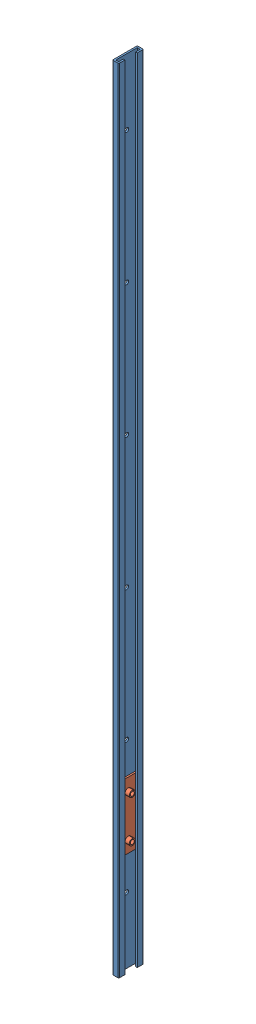
SolidWorks assembly Assem2, configuration Default. Lengths in mm.
Overall size (11.43 1219.2 38.1).
2 component instances, 2 part files, 3 mates.
Components (placement in the parent):
- Slide_Rail-1: Slide_Rail [Default] at (548.5229 0 865.1308) size (9.53 1219.2 38.1)
- Slide_Shoe-1: Slide_Shoe [Default] at (553.6029 256.4411 864.4958) x (-1 0 0) z (0 0 1) size (8.89 101.6 31.75)
Mates (geometry in assembly coordinates):
- Coincident1: coincident aligned: plane of Slide_Rail-1 through (548.5229 0 865.1308) normal (0 1 0); plane of assembly through (0 0 0) normal (0 1 0)
- Width1: width anti-aligned: plane of Slide_Shoe-1 through (553.6029 154.8411 832.7458) normal (0 0 -1); plane of Slide_Shoe-1 through (553.6029 154.8411 864.4958) normal (0 0 1); plane of Slide_Rail-1 through (551.0629 1219.2 832.1108) normal (0 0 1); plane of Slide_Rail-1 through (551.0629 1219.2 865.1308) normal (0 0 -1)
- Coincident3: coincident anti-aligned: plane of Slide_Rail-1 through (551.0629 1219.2 865.1308) normal (1 0 0); plane of Slide_Shoe-1 through (551.0629 154.8411 864.4958) normal (-1 0 0)
